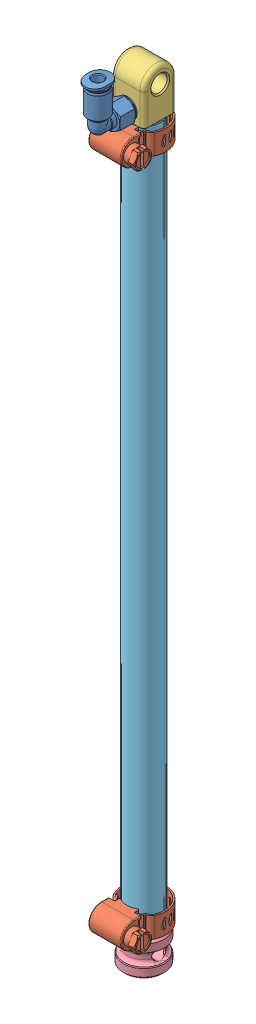
SolidWorks assembly AARL_QR_RL_BA_FL, configuration Default. Lengths in mm.
Overall size (19.43 306.21 31.28).
6 component instances, 5 part files, 15 mates.
Components (placement in the parent):
- AARL_Puppy_18_02_57_010-QSML-M3-4-1: AARL_Puppy_18_02_57_010-QSML-M3-4 [Default] at (-100.6607 139.5847 19.2077) x (0 1 0) z (0 0 -1) size (20.32 8 18.9)
- AARL_Puppy_18_02_57_011-5388K140_Hose-Clamp-1: AARL_Puppy_18_02_57_011-5388K140_Hose-Clamp [5388K14] at (-100.6607 129.8692 1.3577) x (1 0 0) z (0 -1 0) size (19.43 23.71 9.91)
- AARL_Puppy_18_02_57_011-5388K140_Hose-Clamp-2: AARL_Puppy_18_02_57_011-5388K140_Hose-Clamp [5388K14] at (-100.6607 -133.2748 1.3577) x (1 0 0) z (0 -1 0) size (19.43 23.71 9.91)
- AARL_QR_PN_EP_001-1: AARL_QR_PN_EP_001 [Default] at (-100.6607 147.5222 1.3577) x (0 0 1) z (-1 0 0) size (12.7 31.75 12.7)
- AARL_QR_PN_EP_002-1: AARL_QR_PN_EP_002 [Default] at (-100.6607 -138.2278 1.3577) x (-1 0 0) z (0 0 1) size (15.88 25.4 15.88)
- BPA main body 11.5in-1: BPA main body 11.5in [Resting] at (-100.6607 -1.7028 1.3577) size (12.7 273.05 12.7)
Mates (geometry in assembly coordinates):
- Parallel1: parallel aligned: plane of AARL_QR_PN_EP_001-1 through (-107.0107 134.8222 7.7077) normal (0 0 1)
- Concentric2: concentric aligned: cylinder of AARL_Puppy_18_02_57_010-QSML-M3-4-1 through (-100.6607 139.5847 7.7077) axis (0 0 1) radius 1.5; cylinder of AARL_QR_PN_EP_001-1 through (-100.6607 139.5847 7.7077) axis (0 0 1) radius 2.0193
- Perpendicular1: perpendicular: plane of AARL_Puppy_18_02_57_010-QSML-M3-4-1 through (-104.6607 137.2752 14.7633) normal (-1 0 0); plane of AARL_QR_PN_EP_001-1 through (-107.0107 134.8222 -4.9923) normal (0 -1 0)
- Coincident4: coincident anti-aligned: plane of AARL_Puppy_18_02_57_010-QSML-M3-4-1 through (-100.6607 139.5847 7.7077) normal (0 0 -1); plane of AARL_QR_PN_EP_001-1 through (-107.0107 134.8222 7.7077) normal (0 0 1)
- Coincident5: coincident aligned: plane of AARL_Puppy_18_02_57_011-5388K140_Hose-Clamp-1 through (-94.3107 129.8692 11.5914) normal (1 0 0); plane of AARL_QR_PN_EP_001-1 through (-94.3107 147.5222 1.3577) normal (1 0 0)
- Coincident6: coincident anti-aligned: plane of AARL_Puppy_18_02_57_011-5388K140_Hose-Clamp-1 through (-100.6607 134.8222 1.3577) normal (0 1 0); plane of AARL_QR_PN_EP_001-1 through (-107.0107 134.8222 -4.9923) normal (0 -1 0)
- Parallel3: parallel anti-aligned: cylinder of AARL_QR_PN_EP_001-1 through (-107.0107 147.5222 1.3577) axis (1 0 0) radius 3.175; cylinder of AARL_QR_PN_EP_002-1 through (-92.7232 -144.5778 1.3577) axis (-1 0 0) radius 2.3813
- Coincident8: coincident aligned: plane of AARL_Puppy_18_02_57_011-5388K140_Hose-Clamp-1 through (-94.3107 129.8692 11.5914) normal (1 0 0); plane of AARL_Puppy_18_02_57_011-5388K140_Hose-Clamp-2 through (-94.3107 -133.2748 11.5914) normal (1 0 0)
- Coincident9: coincident anti-aligned: plane of AARL_Puppy_18_02_57_011-5388K140_Hose-Clamp-2 through (-100.6607 -138.2278 1.3577) normal (0 -1 0); plane of AARL_QR_PN_EP_002-1 through (-105.0263 -138.2278 1.3577) normal (0 1 0)
- Concentric3: concentric anti-aligned: circle of AARL_QR_PN_EP_001-1; cylinder of BPA main body 11.5in-1 through (-100.6607 9.9057 1.3577) axis (0 1 0) radius 6.35
- Concentric4: concentric aligned: cylinder of AARL_Puppy_18_02_57_011-5388K140_Hose-Clamp-1 through (-100.6607 125.9004 1.3577) axis (0 1 0) radius 8.5217; cylinder of BPA main body 11.5in-1 through (-100.6607 9.9057 1.3577) axis (0 1 0) radius 6.35
- Concentric5: concentric aligned: cylinder of AARL_Puppy_18_02_57_011-5388K140_Hose-Clamp-2 through (-100.6607 -137.2436 1.3577) axis (0 1 0) radius 8.5217; cylinder of BPA main body 11.5in-1 through (-100.6607 9.9057 1.3577) axis (0 1 0) radius 6.35
- Concentric6: concentric aligned: circle of AARL_QR_PN_EP_002-1; cylinder of BPA main body 11.5in-1 through (-100.6607 9.9057 1.3577) axis (0 1 0) radius 6.35
- Coincident10: coincident anti-aligned: plane of AARL_QR_PN_EP_001-1 through (-107.0107 134.8222 -4.9923) normal (0 -1 0); plane of BPA main body 11.5in-1 through (-95.8982 134.8222 1.3577) normal (0 1 0)
- Coincident11: coincident anti-aligned: plane of AARL_QR_PN_EP_002-1 through (-105.0263 -138.2278 1.3577) normal (0 1 0); plane of BPA main body 11.5in-1 through (-94.3107 -138.2278 1.3577) normal (0 -1 0)
